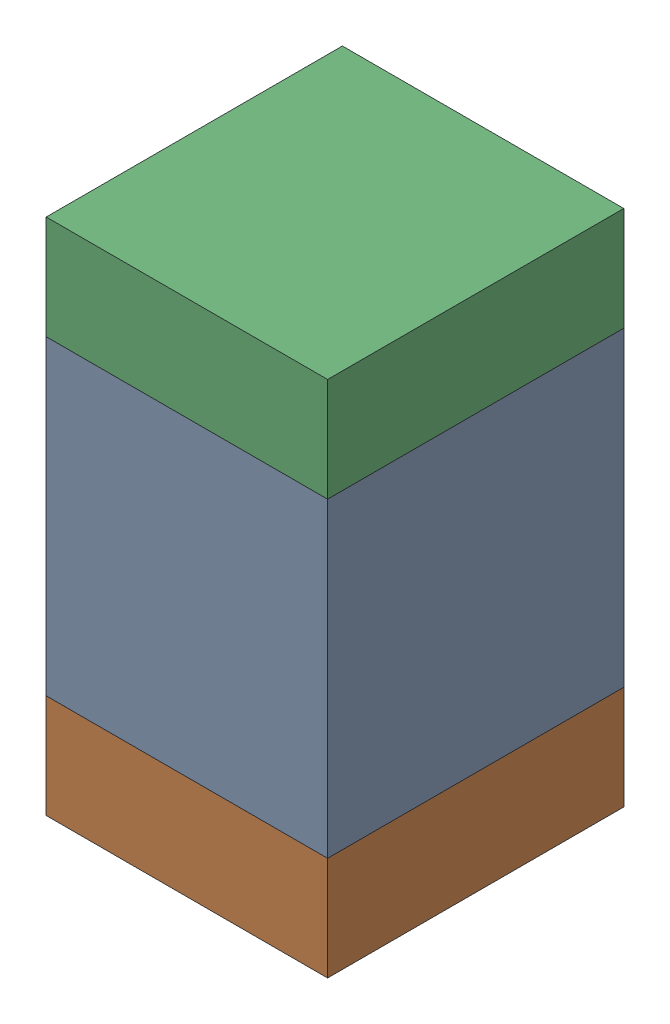
SolidWorks assembly C4-2, configuration Default. Lengths in mm.
Overall size (0.95 1.75 1).
6 component instances, 2 part files, 0 mates.
Components (placement in the parent):
- 959208528-2-1: 959208528-2 [Default] at (127.791 83.885 0) size (0.95 1.05 1)
  - Extruded-77-1: Extruded-77 [Default] at origin size (0.95 1.05 1)
- 959208664-2-1: 959208664-2 [Default] at (127.791 83.185 0) size (0.95 0.35 1)
  - Extruded-76-1: Extruded-76 [Default] at origin size (0.95 0.35 1)
- 959208664-2-2: 959208664-2 [Default] at (127.791 84.585 0) size (0.95 0.35 1)
  - Extruded-76-1: Extruded-76 [Default] at origin size (0.95 0.35 1)
